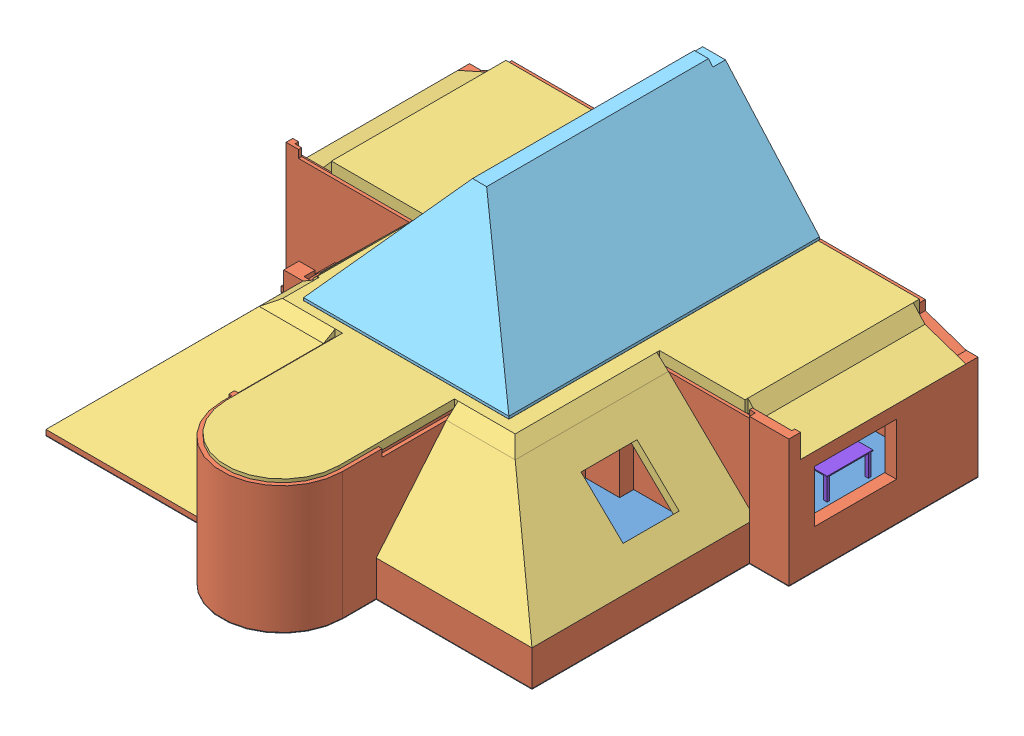
SolidWorks assembly Wohnung, configuration Standard. Lengths in mm.
Overall size (10002 2511 9850.5).
46 component instances, 18 part files, 52 mates.
Components (placement in the parent):
- Grundplatte-1: Grundplatte [Standard] at (1350.1892 -405.6037 9609) size (10002 11 9850.5)
- Wände-1: Wände [Standard] at (-2233.0009 -405.6037 7940.1019) size (10002 2500 9850.5)
- Decke-1: Decke [Standard] at (291.8994 2000.3963 -523.8606) size (10002 2464 9655.75) (hidden)
- Deckenplatte-2: Deckenplatte [Standard] at (1266.1892 2159.3963 7589) size (4039 2 6110) (hidden)
- Decke Wand-1: Decke Wand [Standard] at (727.0307 2160.3963 1192.1442) size (4039.01 2240 6110) (hidden)
- Magnat-Box-1: Magnat-Box [Standard] at (595.2241 -406.6037 7188.7977) x (0.173648 0 -0.984808) z (0.984808 0 0.173648) size (250 855 220)
- Magnat-Box-2: Magnat-Box [Standard] at (5009.1543 -406.6037 7188.7977) x (-0.173648 0 -0.984808) z (0.984808 0 -0.173648) size (250 855 220)
- Panasonic-Tv-1: Panasonic-Tv [Standard] at (2772.8204 233.3963 7131) size (930 670 300)
- Fernseh-tisch-1: Fernseh-tisch [Standard] at (3939.1892 53.3963 5377) x (-1 0 0) z (0 0 1) size (900 460 900)
- Schrank-L-1: Schrank-L [Standard] at (3896.2261 514.6593 9106) x (-1 0 0) z (0 0 -1) size (600 1920 400)
  - Schrank-Korpus-1: Schrank-Korpus [Standard] at (-405.9631 38.7369 1725) size (600 1920 390)
  - Schublade-Hoch-1: Schublade-Hoch [Standard] at (-405.9631 -731.2631 2115) size (600 380 380)
  - Schublade-Tief-1: Schublade-Tief [Standard] at (-405.9631 -411.2631 2115) size (600 260 380)
  - Regalbrett-1: Regalbrett [Standard] at (-405.9631 -286.2631 1735) x (1 0 0) z (0 -1 0) size (560 360 10)
  - Regalbrett-2: Regalbrett [Standard] at (-405.9631 -20.5713 1735) x (1 0 0) z (0 -1 0) size (560 360 10)
  - Regalbrett-3: Regalbrett [Standard] at (-405.9631 223.3159 1735) x (1 0 0) z (0 -1 0) size (560 360 10)
  - Regalbrett-4: Regalbrett [Standard] at (-405.9631 479.3348 1735) x (1 0 0) z (0 -1 0) size (560 360 10)
  - Regalbrett-5: Regalbrett [Standard] at (-405.9631 753.23 1735) x (1 0 0) z (0 -1 0) size (560 360 10)
- Schrank-R-1: Schrank-R [Standard] at (1370.3662 582.8364 9106) x (-1 0 0) z (0 0 -1) size (600 1920 400)
  - Schrank-Korpus-1: Schrank-Korpus [Standard] at (68.177 -29.4401 1725) size (600 1920 390)
  - Türe-1: Türe [Standard] at (68.177 -669.4401 2115) size (600 640 10)
  - Türe-2: Türe [Standard] at (68.177 -29.4401 2115) size (600 640 10)
  - Türe-3: Türe [Standard] at (68.177 610.5599 2115) size (600 640 10)
  - Regalbrett-1: Regalbrett [Standard] at (68.177 -354.4401 2095) x (1 0 0) z (0 1 0) size (560 360 10)
  - Regalbrett-2: Regalbrett [Standard] at (68.177 285.5599 2095) x (1 0 0) z (0 1 0) size (560 360 10)
- Tv-Tisch-L-1: Tv-Tisch-L [Standard] at (3198.6442 -121.7751 8581) x (-1 0 0) z (0 0 -1) size (1200 640 400)
  - TV-Korpus-1: TV-Korpus [Standard] at (-203.545 35.1714 1200) size (1200 640 390)
  - Regalbrett-1: Regalbrett [Standard] at (96.455 -168.3967 1570) x (1 0 0) z (0 1 0) size (560 360 10)
  - Regalbrett-2: Regalbrett [Standard] at (96.455 1.0811 1570) x (1 0 0) z (0 1 0) size (560 360 10)
  - Regalbrett-3: Regalbrett [Standard] at (96.455 171.5058 1570) x (1 0 0) z (0 1 0) size (560 360 10)
  - Schublade-Hoch-1: Schublade-Hoch [Standard] at (-503.545 -94.8286 1590) size (600 380 380)
  - Schublade-Tief-1: Schublade-Tief [Standard] at (-503.545 225.1714 1590) size (600 260 380)
- Tv-Tisch-R-1: Tv-Tisch-R [Standard] at (1998.6442 -121.7751 8581) x (-1 0 0) z (0 0 -1) size (1200 640 400)
  - TV-Korpus-1: TV-Korpus [Standard] at (-203.545 35.1714 1200) size (1200 640 390)
  - Regalbrett-1: Regalbrett [Standard] at (-503.545 -137.2651 1570) x (1 0 0) z (0 1 0) size (560 360 10)
  - Regalbrett-2: Regalbrett [Standard] at (-503.545 10.0754 1570) x (1 0 0) z (0 1 0) size (560 360 10)
  - Regalbrett-3: Regalbrett [Standard] at (-503.545 154.52 1570) x (1 0 0) z (0 1 0) size (560 360 10)
  - Schublade-Hoch-1: Schublade-Hoch [Standard] at (96.455 -94.8286 1590) size (600 380 380)
  - Schublade-Tief-1: Schublade-Tief [Standard] at (96.455 225.1714 1590) size (600 260 380)
- Stuhl-Küche-1: Stuhl-Küche [Standard] at (-341.6443 53.3963 4656.5426) x (0 0 1) z (-1 0 0) size (420 850 490)
- Stuhl-Küche-2: Stuhl-Küche [Standard] at (-1524.4144 53.3963 5156.9607) x (0 0 -1) z (1 0 0) size (420 850 490)
- Stuhl-Küche-3: Stuhl-Küche [Standard] at (-331.5967 53.3963 5201.7309) x (0 0 1) z (-1 0 0) size (420 850 490)
- Stuhl-Küche-4: Stuhl-Küche [Standard] at (-1525.5221 53.3963 4633.9248) x (0 0 -1) z (1 0 0) size (420 850 490)
- Arbeitsplatte-1: Arbeitsplatte [Standard] at (-2598.8108 456.3963 7057) x (-1 0 0) z (0 0 -1) size (3508 926 620)
- Schrank_L-1: Schrank_L [Standard] at (-1802.3108 932.3963 7182.5) size (1793 927 369)
- Schrank_R-1: Schrank_R [Standard] at (-3391.8108 932.3963 7179.5) size (300 921 375)
Mates (geometry in assembly coordinates):
- Deckungsgleich3: coincident anti-aligned: plane of Grundplatte-1 through (1350.1892 -405.6037 9609) normal (0 1 0); plane of Wände-1 through (391.6892 -405.6037 12550) normal (0 -1 0)
- Deckungsgleich4: coincident aligned: line of Grundplatte-1 through (1437.1892 -405.6037 9472) axis (0 0 -1); line of Wände-1 through (1437.1892 -405.6037 9472) axis (0 0 -1)
- Deckungsgleich5: coincident anti-aligned: line of Grundplatte-1 through (1437.1892 -405.6037 9472) axis (-1 0 0); line of Wände-1 through (1212.1892 -405.6037 9472) axis (1 0 0)
- Deckungsgleich6: coincident anti-aligned: plane of Wände-1 through (-2233.0009 2000.3963 7940.1019) normal (0 1 0); plane of Decke-1 through (291.8994 2000.3963 -523.8606) normal (0 -1 0)
- Deckungsgleich7: coincident aligned: plane of Wände-1 through (-909.3108 5433.3963 7437.5) normal (-1 0 0); line of Decke-1 through (-909.3108 2000.3963 7437.5) axis (0 0 1)
- Deckungsgleich9: coincident anti-aligned: plane of Wände-1 through (1509.6892 2150.3963 9540.5) normal (0 0 -1); plane of Decke-1 through (-909.3108 2158.3963 9540.5) normal (0 0 1)
- Deckungsgleich15: coincident anti-aligned: line of Decke-1 through (1266.1892 2158.3963 7589) axis (-1 0 0); line of Deckenplatte-2 through (-50.8108 2158.3963 7589) axis (1 0 0)
- Deckungsgleich16: coincident anti-aligned: line of Decke-1 through (1266.1892 2158.3963 8203) axis (0 0 -1); line of Deckenplatte-2 through (1266.1892 2158.3963 7589) axis (0 0 1)
- Deckungsgleich17: coincident aligned: line of Deckenplatte-2 through (-1647.8108 2160.3963 3980) axis (0 0 1); line of Decke Wand-1 through (-1647.8108 2160.3963 3980) axis (0 0 1)
- Deckungsgleich18: coincident aligned: line of Deckenplatte-2 through (-1647.8108 2160.3963 10090) axis (1 0 0); line of Decke Wand-1 through (-1647.8108 2160.3963 10090) axis (1 0 0)
- Deckungsgleich19: coincident anti-aligned: plane of Grundplatte-1 through (391.6892 -406.6037 12550) normal (0 1 0); plane of Magnat-Box-1 through (595.2241 -406.6037 7188.7977) normal (0 -1 0)
- Deckungsgleich20: coincident anti-aligned: plane of Grundplatte-1 through (391.6892 -406.6037 12550) normal (0 1 0); plane of Magnat-Box-2 through (5009.1543 -406.6037 7188.7977) normal (0 -1 0)
- Winkel1: planar angle = 0.174533 rad anti-aligned: plane of Magnat-Box-2 through (5139.1892 448.3963 7292.7974) normal (0.173648 0 0.984808); plane of Wände-1 through (415.1892 2094.3963 7381) normal (0 0 -1)
- Abstand2: distance = 50 mm: line of Magnat-Box-2 through (4922.5315 448.3963 7331) axis (0 -1 0); plane of Wände-1 through (415.1892 2094.3963 7381) normal (0 0 -1)
- Abstand3: distance = 50 mm: line of Magnat-Box-2 through (5139.1892 448.3963 7292.7974) axis (0 -1 0); plane of Wände-1 through (5189.1892 2094.3963 7381) normal (-1 0 0)
- Winkel2: planar angle = 0.174533 rad anti-aligned: plane of Wände-1 through (415.1892 2094.3963 7381) normal (0 0 -1); plane of Magnat-Box-1 through (681.8469 448.3963 7331) normal (-0.173648 0 0.984808)
- Abstand4: distance = 50 mm: line of Magnat-Box-1 through (681.8469 448.3963 7331) axis (0 -1 0); plane of Wände-1 through (415.1892 2094.3963 7381) normal (0 0 -1)
- Abstand5: distance = 50 mm: plane of Wände-1 through (415.1892 2094.3963 6505) normal (1 0 0); line of Magnat-Box-1 through (465.1892 448.3963 7292.7974) axis (0 -1 0)
- Abstand6: distance = 100 mm anti-aligned: plane of Panasonic-Tv-1 through (2572.8204 273.3963 7281) normal (0 0 1); plane of Wände-1 through (415.1892 2094.3963 7381) normal (0 0 -1)
- Deckungsgleich30: coincident anti-aligned: plane of Grundplatte-1 through (391.6892 -406.6037 12550) normal (0 1 0); plane of Fernseh-tisch-1 through (3939.1892 -406.6037 5377) normal (0 -1 0)
- Abstand8: distance = 800 mm anti-aligned: plane of Fernseh-tisch-1 through (4389.1892 33.3963 4927) normal (0 0 -1); plane of Wände-1 through (5189.1892 2094.3963 4127) normal (0 0 1)
- Abstand9: distance = 800 mm anti-aligned: plane of Wände-1 through (5189.1892 2094.3963 7381) normal (-1 0 0); plane of Fernseh-tisch-1 through (4389.1892 33.3963 5827) normal (1 0 0)
- Deckungsgleich33: coincident anti-aligned: plane of Grundplatte-1 through (391.6892 -406.6037 12550) normal (0 1 0); plane of Stuhl-Küche-4 through (-1525.5221 -406.6037 4633.9248) normal (0 -1 0)
- Deckungsgleich34: coincident anti-aligned: plane of Grundplatte-1 through (391.6892 -406.6037 12550) normal (0 1 0); plane of Stuhl-Küche-1 through (-341.6443 -406.6037 4656.5426) normal (0 -1 0)
- Deckungsgleich35: coincident anti-aligned: plane of Grundplatte-1 through (391.6892 -406.6037 12550) normal (0 1 0); plane of Stuhl-Küche-2 through (-1524.4144 -406.6037 5156.9607) normal (0 -1 0)
- Deckungsgleich36: coincident anti-aligned: plane of Grundplatte-1 through (391.6892 -406.6037 12550) normal (0 1 0); plane of Stuhl-Küche-3 through (-331.5967 -406.6037 5201.7309) normal (0 -1 0)
- Parallel1: parallel: plane of Wände-1 through (123.1892 2094.3963 5732) normal (-1 0 0); line of Stuhl-Küche-1 through (-151.6443 73.3963 4826.5426) axis (0 0 -1)
- Parallel2: parallel: plane of Wände-1 through (123.1892 2094.3963 5732) normal (-1 0 0); line of Stuhl-Küche-3 through (-141.5967 73.3963 5371.7309) axis (0 0 -1)
- Parallel5: parallel: plane of Wände-1 through (123.1892 2094.3963 5732) normal (-1 0 0); line of Stuhl-Küche-4 through (-1335.5221 73.3963 4843.9248) axis (0 0 -1)
- Parallel6: parallel: plane of Wände-1 through (123.1892 2094.3963 5732) normal (-1 0 0); line of Stuhl-Küche-2 through (-1334.4144 73.3963 5366.9607) axis (0 0 -1)
- Deckungsgleich37: coincident anti-aligned: plane of Wände-1 through (-4352.8108 2094.3963 7367) normal (0 0 -1); plane of Arbeitsplatte-1 through (-844.8108 494.3963 7367) normal (0 0 1)
- Deckungsgleich38: coincident anti-aligned: plane of Wände-1 through (-4352.8108 2094.3963 4120) normal (1 0 0); plane of Arbeitsplatte-1 through (-4352.8108 494.3963 6747) normal (-1 0 0)
- Deckungsgleich39: coincident anti-aligned: plane of Grundplatte-1 through (391.6892 -406.6037 12550) normal (0 1 0); plane of Arbeitsplatte-1 through (-2598.8108 -406.6037 7057) normal (0 -1 0)
- Deckungsgleich40: coincident aligned: plane of Arbeitsplatte-1 through (-844.8108 494.3963 6747) normal (1 0 0); plane of Schrank_L-1 through (-844.8108 952.3963 7120) normal (1 0 0)
- Deckungsgleich41: coincident anti-aligned: plane of Wände-1 through (-4352.8108 2094.3963 7367) normal (0 0 -1); plane of Schrank_L-1 through (-844.8108 952.3963 7367) normal (0 0 1)
- Abstand10: distance = 438 mm anti-aligned: plane of Arbeitsplatte-1 through (-2598.8108 494.3963 7057) normal (0 1 0); plane of Schrank_L-1 through (-1802.3108 932.3963 7182.5) normal (0 -1 0)
- Deckungsgleich43: coincident anti-aligned: plane of Wände-1 through (-4352.8108 2094.3963 7367) normal (0 0 -1); plane of Schrank_R-1 through (-3541.8108 1853.3963 7367) normal (0 0 1)
- Deckungsgleich44: coincident aligned: plane of Schrank_L-1 through (-1802.3108 932.3963 7182.5) normal (0 -1 0); plane of Schrank_R-1 through (-3391.8108 932.3963 7179.5) normal (0 -1 0)
- Abstand11: distance = 604 mm anti-aligned: plane of Schrank_L-1 through (-2637.8108 952.3963 7367) normal (-1 0 0); plane of Schrank_R-1 through (-3241.8108 1853.3963 7367) normal (1 0 0)
- Deckungsgleich46: coincident anti-aligned: plane of Wände-1 through (415.1892 2094.3963 7381) normal (0 0 -1); plane of Tv-Tisch-L-1/TV-Korpus-1 through (3402.1892 -86.6037 7381) normal (0 0 1)
- Deckungsgleich47: coincident anti-aligned: plane of Wände-1 through (415.1892 2094.3963 7381) normal (0 0 -1); plane of Tv-Tisch-R-1/TV-Korpus-1 through (2202.1892 -86.6037 7381) normal (0 0 1)
- Deckungsgleich48: coincident anti-aligned: plane of Wände-1 through (415.1892 2094.3963 7381) normal (0 0 -1); plane of Schrank-R-1/Schrank-Korpus-1 through (1302.1892 553.3963 7381) normal (0 0 1)
- Deckungsgleich49: coincident anti-aligned: plane of Wände-1 through (415.1892 2094.3963 7381) normal (0 0 -1); plane of Schrank-L-1/Schrank-Korpus-1 through (4302.1892 553.3963 7381) normal (0 0 1)
- Deckungsgleich50: coincident anti-aligned: plane of Grundplatte-1 through (391.6892 -406.6037 12550) normal (0 1 0); plane of Schrank-L-1/Schrank-Korpus-1 through (4602.1892 -406.6037 7371) normal (0 -1 0)
- Deckungsgleich51: coincident anti-aligned: plane of Schrank-L-1/Schrank-Korpus-1 through (4002.1892 -406.6037 7371) normal (-1 0 0); plane of Tv-Tisch-L-1/TV-Korpus-1 through (4002.1892 -406.6037 7371) normal (1 0 0)
- Deckungsgleich52: coincident anti-aligned: plane of Tv-Tisch-L-1/TV-Korpus-1 through (2802.1892 -406.6037 7371) normal (-1 0 0); plane of Tv-Tisch-R-1/TV-Korpus-1 through (2802.1892 -406.6037 7371) normal (1 0 0)
- Deckungsgleich53: coincident anti-aligned: plane of Schrank-R-1/Schrank-Korpus-1 through (1602.1892 -406.6037 7371) normal (1 0 0); plane of Tv-Tisch-R-1/TV-Korpus-1 through (1602.1892 -406.6037 7371) normal (-1 0 0)
- Deckungsgleich55: coincident anti-aligned: plane of Grundplatte-1 through (391.6892 -406.6037 12550) normal (0 1 0); plane of Tv-Tisch-L-1/TV-Korpus-1 through (4002.1892 -406.6037 7371) normal (0 -1 0)
- Deckungsgleich56: coincident anti-aligned: plane of Grundplatte-1 through (391.6892 -406.6037 12550) normal (0 1 0); plane of Tv-Tisch-R-1/TV-Korpus-1 through (2802.1892 -406.6037 7371) normal (0 -1 0)
- Deckungsgleich57: coincident anti-aligned: plane of Grundplatte-1 through (391.6892 -406.6037 12550) normal (0 1 0); plane of Schrank-R-1/Schrank-Korpus-1 through (1602.1892 -406.6037 7371) normal (0 -1 0)
- Deckungsgleich58: coincident anti-aligned: plane of Panasonic-Tv-1 through (2772.8204 233.3963 7131) normal (0 -1 0); plane of Tv-Tisch-L-1/TV-Korpus-1 through (4002.1892 233.3963 7371) normal (0 1 0)
- Abstand12: distance = 587 mm anti-aligned: plane of Schrank-L-1/Schrank-Korpus-1 through (4602.1892 -406.6037 7371) normal (1 0 0); plane of Wände-1 through (5189.1892 2094.3963 7381) normal (-1 0 0)
